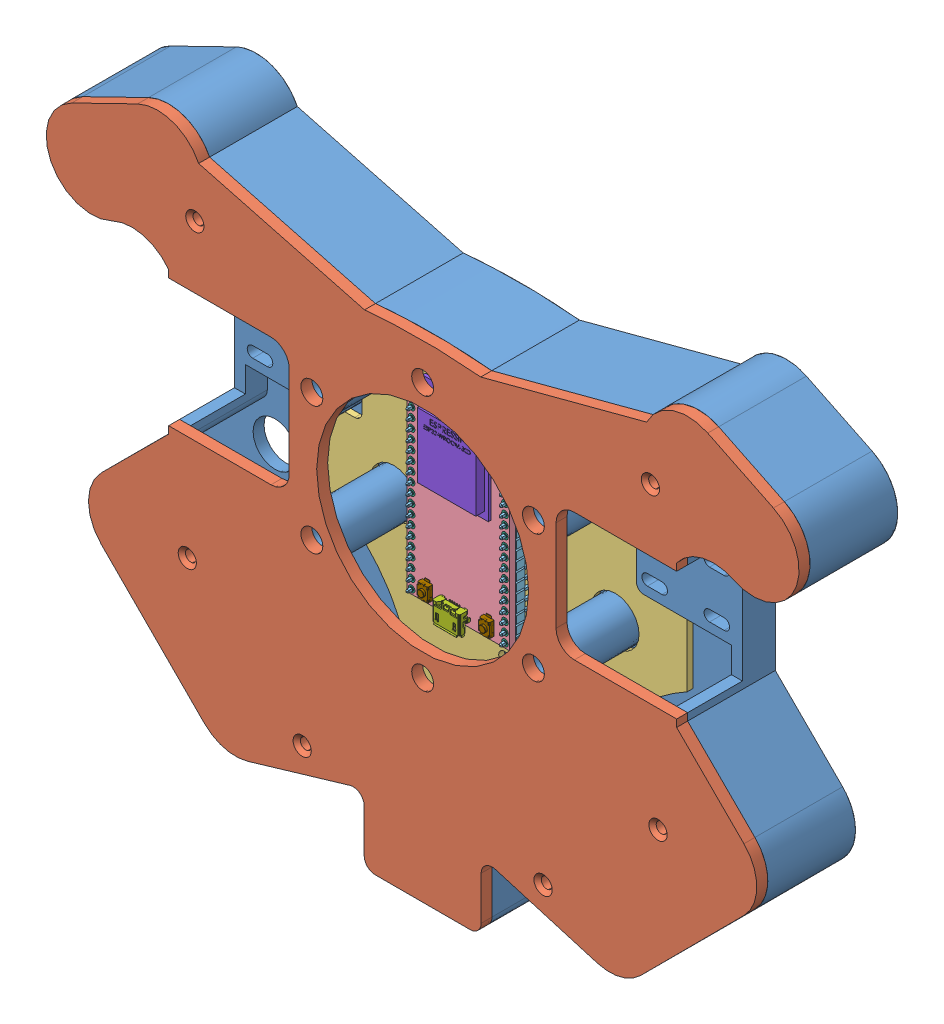
SolidWorks assembly Assembly, configuration 默认. Lengths in mm.
Overall size (206.04 156.46 27.06).
35 component instances, 14 part files, 12 mates.
Components (placement in the parent):
- button_plate_rev_1-1: button_plate_rev_1 [默认] at (-81.8949 44.4382 -10.4705) size (206.04 151.46 24.07)
- button_plate_lid_rev1-1: button_plate_lid_rev1 [默认] at (-81.8949 44.4382 13.5295) size (206 151.44 5)
- PCB_assembly-1: PCB_assembly [默认] at (-24.3549 21.7004 -6.6705) size (100 100 17.98)
  - PCB-1: PCB [默认] at (-57.54 22.7378 -0.8) size (100 100 1.6)
  - ESP32-WROOM-32D-1: ESP32-WROOM-32D [默认] at (-57.54 20.4078 11.84) x (1 0 0) z (0 -1 0) size (28.1 14.23 54.86)
    - Main-PCB.STEP-1: Main-PCB.STEP [默认] x (1 0 0) z (0 1 0) size (28.1 48.26 1.6)
    - zl201-19_p2-54_l48-3_w2-54_h8-9.STEP-1: zl201-19_p2-54_l48-3_w2-54_h8-9.STEP [默认] at (-12.78 -0.25 22.86) x (0 0 1) z (0 -1 0) size (48.26 2.54 11.94)
    - zl201-19_p2-54_l48-3_w2-54_h8-9.STEP-2: zl201-19_p2-54_l48-3_w2-54_h8-9.STEP [默认] at (12.78 -0.25 -22.86) x (0 0 -1) z (0 -1 0) size (48.26 2.54 11.94)
    - Soldering-Contacts.STEP-1: Soldering-Contacts.STEP [默认] at (0 1.6 0) x (1 0 0) z (0 1 0) size (27.34 47.52 2)
    - ab2_usb_micro_smd.wrl.STEP-1: ab2_usb_micro_smd.wrl.STEP [默认] at (0 2.585 24.73) x (1 0 0) z (0 1 0) size (8 5.6 3.57)
    - ESP32-chip.STEP-1: ESP32-chip.STEP [默认] at (0 1.6 0) x (1 0 0) z (0 1 0) size (18 25.8 3.2)
    - 3x4x2mm_tact_button.STEP-1: 3x4x2mm_tact_button.STEP [默认] at (9.1347 1.6 18.3459) x (0 0 1) z (-1 0 0) size (5 2 2.9)
    - 3x4x2mm_tact_button.STEP-2: 3x4x2mm_tact_button.STEP [默认] at (-7.7053 1.6 18.3459) x (0 0 1) z (-1 0 0) size (5 2 2.9)
- type_c_test_board-1: type_c_test_board [默认] at (-10.9089 -34.836 -2.9156) x (1 0 0) z (0 -1 0) size (22 4.76 15)
  - type_c_motherboard-1: type_c_motherboard [默认] at (-70.9859 7.4452 0) size (22 1.6 13.8)
  - USB Type C Socket^PCB_Riden TC64 Module 01a(2)_Riden TC64 Module 01a-1: USB Type C Socket^PCB_Riden TC64 Module 01a(2)_Riden TC64 Module 01a [默认] at (-70.9859 10.6252 5.15) size (8.95 3.16 7.36)
    - USB_C_SHELL^USB Type C Socket_PCB_Riden TC64 Module 01a(2)_Riden TC64 Module 01a-1: USB_C_SHELL^USB Type C Socket_PCB_Riden TC64 Module 01a(2)_Riden TC64 Module 01a [默认] at origin size (8.95 3.16 5.9) (virtual)
    - USB_C_Body^USB Type C Socket_PCB_Riden TC64 Module 01a(2)_Riden TC64 Module 01a-1: USB_C_Body^USB Type C Socket_PCB_Riden TC64 Module 01a(2)_Riden TC64 Module 01a [默认] at (0 0 -1.21) size (8.77 3.06 6.05) (virtual)
    - USB_C_PIN^USB Type C Socket_PCB_Riden TC64 Module 01a(2)_Riden TC64 Module 01a-1: USB_C_PIN^USB Type C Socket_PCB_Riden TC64 Module 01a(2)_Riden TC64 Module 01a [默认] at (3 0.5 -3.47) x (-1 0 0) z (0 -1 0) size (0.3 1.94 0.21) (virtual)
    - USB_C_PIN^USB Type C Socket_PCB_Riden TC64 Module 01a(2)_Riden TC64 Module 01a-2: USB_C_PIN^USB Type C Socket_PCB_Riden TC64 Module 01a(2)_Riden TC64 Module 01a [默认] at (2.2 0.5 -3.47) x (-1 0 0) z (0 -1 0) size (0.3 1.94 0.21) (virtual)
    - USB_C_PIN^USB Type C Socket_PCB_Riden TC64 Module 01a(2)_Riden TC64 Module 01a-3: USB_C_PIN^USB Type C Socket_PCB_Riden TC64 Module 01a(2)_Riden TC64 Module 01a [默认] at (1.4 0.5 -3.47) x (-1 0 0) z (0 -1 0) size (0.3 1.94 0.21) (virtual)
    - USB_C_PIN^USB Type C Socket_PCB_Riden TC64 Module 01a(2)_Riden TC64 Module 01a-4: USB_C_PIN^USB Type C Socket_PCB_Riden TC64 Module 01a(2)_Riden TC64 Module 01a [默认] at (0.6 0.5 -3.47) x (-1 0 0) z (0 -1 0) size (0.3 1.94 0.21) (virtual)
    - USB_C_PIN^USB Type C Socket_PCB_Riden TC64 Module 01a(2)_Riden TC64 Module 01a-5: USB_C_PIN^USB Type C Socket_PCB_Riden TC64 Module 01a(2)_Riden TC64 Module 01a [默认] at (-0.2 0.5 -3.47) x (-1 0 0) z (0 -1 0) size (0.3 1.94 0.21) (virtual)
    - USB_C_PIN^USB Type C Socket_PCB_Riden TC64 Module 01a(2)_Riden TC64 Module 01a-6: USB_C_PIN^USB Type C Socket_PCB_Riden TC64 Module 01a(2)_Riden TC64 Module 01a [默认] at (-2.6 0.5 -3.47) x (-1 0 0) z (0 -1 0) size (0.3 1.94 0.21) (virtual)
    - USB_C_PIN^USB Type C Socket_PCB_Riden TC64 Module 01a(2)_Riden TC64 Module 01a-7: USB_C_PIN^USB Type C Socket_PCB_Riden TC64 Module 01a(2)_Riden TC64 Module 01a [默认] at (-1.8 0.5 -3.47) x (-1 0 0) z (0 -1 0) size (0.3 1.94 0.21) (virtual)
    - USB_C_PIN^USB Type C Socket_PCB_Riden TC64 Module 01a(2)_Riden TC64 Module 01a-8: USB_C_PIN^USB Type C Socket_PCB_Riden TC64 Module 01a(2)_Riden TC64 Module 01a [默认] at (-3 -0.45 -3.45) x (1 0 0) z (0 1 0) size (0.3 1.94 0.21) (virtual)
    - USB_C_PIN^USB Type C Socket_PCB_Riden TC64 Module 01a(2)_Riden TC64 Module 01a-9: USB_C_PIN^USB Type C Socket_PCB_Riden TC64 Module 01a(2)_Riden TC64 Module 01a [默认] at (-2.2 -0.45 -3.45) x (1 0 0) z (0 1 0) size (0.3 1.94 0.21) (virtual)
    - USB_C_PIN^USB Type C Socket_PCB_Riden TC64 Module 01a(2)_Riden TC64 Module 01a-10: USB_C_PIN^USB Type C Socket_PCB_Riden TC64 Module 01a(2)_Riden TC64 Module 01a [默认] at (-1.4 -0.45 -3.45) x (1 0 0) z (0 1 0) size (0.3 1.94 0.21) (virtual)
    - USB_C_PIN^USB Type C Socket_PCB_Riden TC64 Module 01a(2)_Riden TC64 Module 01a-11: USB_C_PIN^USB Type C Socket_PCB_Riden TC64 Module 01a(2)_Riden TC64 Module 01a [默认] at (-0.6 -0.45 -3.45) x (1 0 0) z (0 1 0) size (0.3 1.94 0.21) (virtual)
    - USB_C_PIN^USB Type C Socket_PCB_Riden TC64 Module 01a(2)_Riden TC64 Module 01a-12: USB_C_PIN^USB Type C Socket_PCB_Riden TC64 Module 01a(2)_Riden TC64 Module 01a [默认] at (1 -0.45 -3.45) x (1 0 0) z (0 1 0) size (0.3 1.94 0.21) (virtual)
    - USB_C_PIN^USB Type C Socket_PCB_Riden TC64 Module 01a(2)_Riden TC64 Module 01a-13: USB_C_PIN^USB Type C Socket_PCB_Riden TC64 Module 01a(2)_Riden TC64 Module 01a [默认] at (0.2 -0.45 -3.45) x (1 0 0) z (0 1 0) size (0.3 1.94 0.21) (virtual)
    - USB_C_PIN^USB Type C Socket_PCB_Riden TC64 Module 01a(2)_Riden TC64 Module 01a-14: USB_C_PIN^USB Type C Socket_PCB_Riden TC64 Module 01a(2)_Riden TC64 Module 01a [默认] at (1.8 -0.45 -3.45) x (1 0 0) z (0 1 0) size (0.3 1.94 0.21) (virtual)
    - USB_C_PIN^USB Type C Socket_PCB_Riden TC64 Module 01a(2)_Riden TC64 Module 01a-15: USB_C_PIN^USB Type C Socket_PCB_Riden TC64 Module 01a(2)_Riden TC64 Module 01a [默认] at (2.6 -0.45 -3.45) x (1 0 0) z (0 1 0) size (0.3 1.94 0.21) (virtual)
    - USB_C_PIN^USB Type C Socket_PCB_Riden TC64 Module 01a(2)_Riden TC64 Module 01a-16: USB_C_PIN^USB Type C Socket_PCB_Riden TC64 Module 01a(2)_Riden TC64 Module 01a [默认] at (-1 0.5 -3.47) x (-1 0 0) z (0 -1 0) size (0.3 1.94 0.21) (virtual)
- SS12D06_switch-1: SS12D06_switch [默认] at (-81.6449 -37.436 -1.1205) x (-1 0 0) z (0 0 1) size (12.7 18.2 6.7)
Mates (geometry in assembly coordinates):
- 重合1: coincident anti-aligned: plane of button_plate_rev_1-1 through (-81.8949 44.4382 13.5295) normal (0 0 1); plane of button_plate_lid_rev1-1 through (-81.8949 38.6427 13.5295) normal (0 0 -1)
- 同心1: concentric anti-aligned: cylinder of button_plate_rev_1-1 through (-81.8949 79.4382 -7.4705) axis (0 0 -1) radius 3; cylinder of button_plate_lid_rev1-1 through (-81.8949 79.4382 5013.5295) axis (0 0 1) radius 3
- 同心2: concentric anti-aligned: cylinder of button_plate_rev_1-1 through (-81.8949 9.4382 -7.4705) axis (0 0 -1) radius 3; cylinder of button_plate_lid_rev1-1 through (-81.8949 9.4382 5013.5295) axis (0 0 1) radius 3
- 重合2: coincident anti-aligned: plane of button_plate_rev_1-1 through (-136.0637 -34.3736 -7.4705) normal (0 0 1); plane of PCB_assembly-1/PCB-1 through (-113.5918 3.1857 -7.4705) normal (0 0 -1)
- 同心3: concentric anti-aligned: cylinder of button_plate_rev_1-1 through (-112.2058 61.9382 30.5001) axis (0 0 -1) radius 6; circle of PCB_assembly-1/PCB-1
- 同心4: concentric anti-aligned: cylinder of button_plate_rev_1-1 through (-51.584 26.9382 30.5001) axis (0 0 -1) radius 6; circle of PCB_assembly-1/PCB-1
- 重合3: coincident anti-aligned: plane of button_plate_rev_1-1 through (-81.8949 44.4382 4.5295) normal (0 0 1); plane of type_c_test_board-1/type_c_motherboard-1 through (-81.8949 -34.836 4.5295) normal (0 0 -1)
- 重合4: coincident anti-aligned: circle of button_plate_rev_1-1; cylinder of type_c_test_board-1/type_c_motherboard-1 through (-73.1949 -39.236 6.1295) axis (0 0 -1) radius 1.5
- 同心5: concentric aligned: circle of button_plate_rev_1-1; circle of type_c_test_board-1/type_c_motherboard-1
- 重合7: coincident anti-aligned: plane of button_plate_rev_1-1 through (-88.4949 -26.7001 -4.4705) normal (0 0 1); plane of SS12D06_switch-1 through (-75.2949 -43.736 -4.4705) normal (0 0 -1)
- 重合8: coincident anti-aligned: plane of button_plate_rev_1-1 through (-75.2949 -26.7001 -4.4705) normal (-1 0 0); plane of SS12D06_switch-1 through (-75.2949 -43.736 -4.4705) normal (1 0 0)
- 重合10: coincident aligned: plane of button_plate_rev_1-1 through (-97.8949 -43.736 -7.4705) normal (0 -1 0); plane of SS12D06_switch-1 through (-81.6449 -43.736 -1.1205) normal (0 -1 0)
